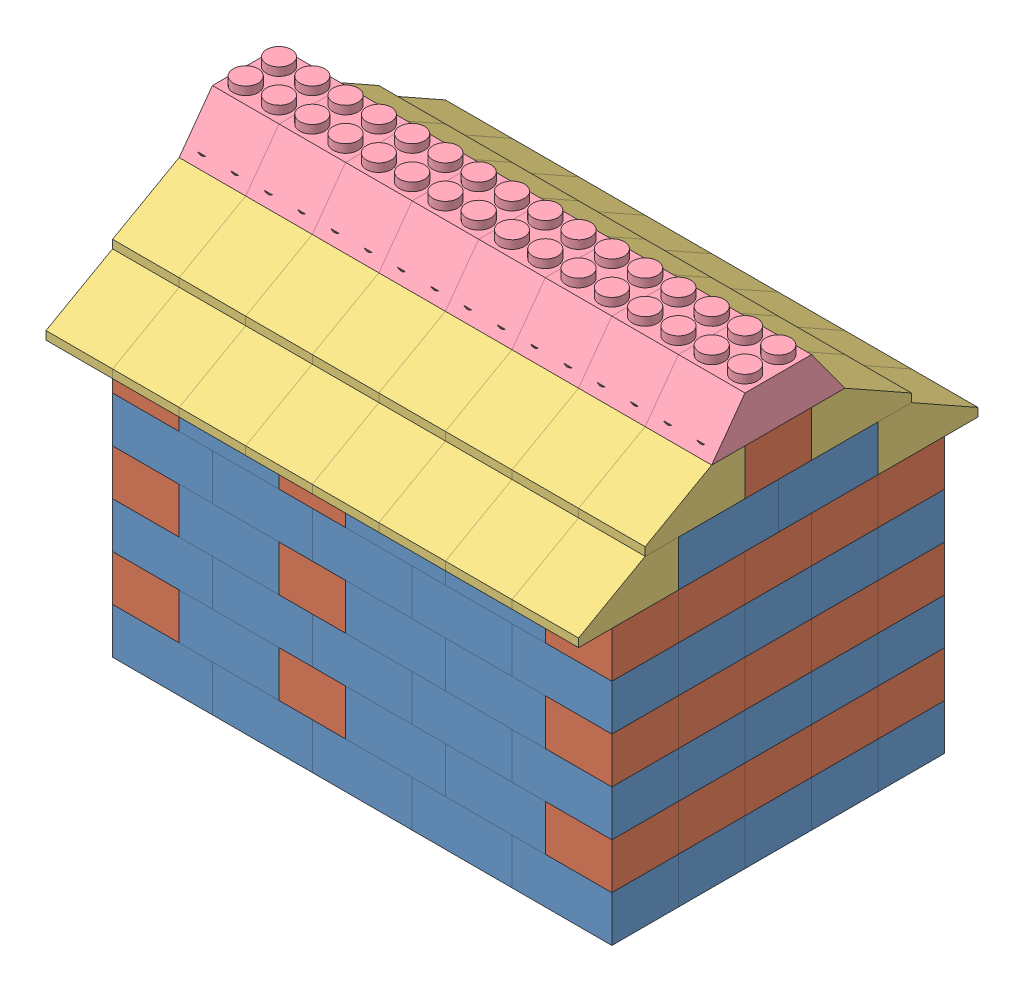
SolidWorks assembly huisje, configuration Default. Lengths in mm.
Overall size (128 101 96).
229 component instances, 4 part files, 42 mates.
Components (placement in the parent):
- lego blokje-1: lego blokje [Default] at origin size (24 13 16)
- lego blokje-2: lego blokje [Default] at (24 0 0) size (24 13 16)
- lego blokje-3: lego blokje [Default] at (48 0 0) size (24 13 16)
- lego blokje-4: lego blokje [Default] at (72 0 0) size (24 13 16)
- lego blokje-5: lego blokje [Default] at (96 0 0) size (24 13 16)
- vierkant blokje lego-3: vierkant blokje lego [Default] at (-4 16.5 -8) size (16 13 16)
- lego blokje-6: lego blokje [Default] at (16 11 0) size (24 13 16)
- vierkant blokje lego-4: vierkant blokje lego [Default] at (36 16.5 -8) size (16 13 16)
- lego blokje-7: lego blokje [Default] at (56 11 0) size (24 13 16)
- lego blokje-8: lego blokje [Default] at (80 11 0) size (24 13 16)
- vierkant blokje lego-5: vierkant blokje lego [Default] at (100 16.5 -8) size (16 13 16)
- lego blokje-9: lego blokje [Default] at (96 22 0) size (24 13 16)
- lego blokje-10: lego blokje [Default] at (96 44 0) size (24 13 16)
- lego blokje-11: lego blokje [Default] at (24 22 0) size (24 13 16)
- lego blokje-12: lego blokje [Default] at (24 44 0) size (24 13 16)
- lego blokje-13: lego blokje [Default] at (48 22 0) size (24 13 16)
- lego blokje-14: lego blokje [Default] at (48 44 0) size (24 13 16)
- lego blokje-15: lego blokje [Default] at (72 22 0) size (24 13 16)
- lego blokje-16: lego blokje [Default] at (72 44 0) size (24 13 16)
- vierkant blokje lego-6: vierkant blokje lego [Default] at (100 38.5 -8) size (16 13 16)
- vierkant blokje lego-7: vierkant blokje lego [Default] at (100 60.5 -8) size (16 13 16)
- vierkant blokje lego-8: vierkant blokje lego [Default] at (36 38.5 -8) size (16 13 16)
- vierkant blokje lego-9: vierkant blokje lego [Default] at (36 60.5 -8) size (16 13 16)
- lego blokje-17: lego blokje [Default] at (0 22 0) size (24 13 16)
- lego blokje-18: lego blokje [Default] at (0 44 0) size (24 13 16)
- vierkant blokje lego-10: vierkant blokje lego [Default] at (-4 38.5 -8) size (16 13 16)
- vierkant blokje lego-11: vierkant blokje lego [Default] at (-4 60.5 -8) size (16 13 16)
- lego blokje-19: lego blokje [Default] at (16 33 0) size (24 13 16)
- lego blokje-20: lego blokje [Default] at (16 55 0) size (24 13 16)
- lego blokje-21: lego blokje [Default] at (56 33 0) size (24 13 16)
- lego blokje-22: lego blokje [Default] at (56 55 0) size (24 13 16)
- lego blokje-23: lego blokje [Default] at (80 33 0) size (24 13 16)
- lego blokje-24: lego blokje [Default] at (80 55 0) size (24 13 16)
- lego blokje-25: lego blokje [Default] at (96 0 -16) size (24 13 16)
- lego blokje-26: lego blokje [Default] at (96 0 -32) size (24 13 16)
- lego blokje-27: lego blokje [Default] at (96 0 -48) size (24 13 16)
- lego blokje-28: lego blokje [Default] at (96 0 -64) size (24 13 16)
- lego blokje-29: lego blokje [Default] at (24 0 -16) size (24 13 16)
- lego blokje-30: lego blokje [Default] at (24 0 -32) size (24 13 16)
- lego blokje-31: lego blokje [Default] at (24 0 -48) size (24 13 16)
- lego blokje-32: lego blokje [Default] at (24 0 -64) size (24 13 16)
- lego blokje-33: lego blokje [Default] at (48 0 -16) size (24 13 16)
- lego blokje-34: lego blokje [Default] at (48 0 -32) size (24 13 16)
- lego blokje-35: lego blokje [Default] at (48 0 -48) size (24 13 16)
- lego blokje-36: lego blokje [Default] at (48 0 -64) size (24 13 16)
- lego blokje-37: lego blokje [Default] at (72 0 -16) size (24 13 16)
- lego blokje-38: lego blokje [Default] at (72 0 -32) size (24 13 16)
- lego blokje-39: lego blokje [Default] at (72 0 -48) size (24 13 16)
- lego blokje-40: lego blokje [Default] at (72 0 -64) size (24 13 16)
- lego blokje-41: lego blokje [Default] at (96 22 -16) size (24 13 16)
- lego blokje-42: lego blokje [Default] at (96 22 -32) size (24 13 16)
- lego blokje-43: lego blokje [Default] at (96 22 -48) size (24 13 16)
- lego blokje-44: lego blokje [Default] at (96 22 -64) size (24 13 16)
- lego blokje-45: lego blokje [Default] at (96 44 -16) size (24 13 16)
- lego blokje-46: lego blokje [Default] at (96 44 -32) size (24 13 16)
- lego blokje-47: lego blokje [Default] at (96 44 -48) size (24 13 16)
- lego blokje-48: lego blokje [Default] at (96 44 -64) size (24 13 16)
- lego blokje-49: lego blokje [Default] at (24 22 -16) size (24 13 16)
- lego blokje-50: lego blokje [Default] at (24 22 -32) size (24 13 16)
- lego blokje-51: lego blokje [Default] at (24 22 -48) size (24 13 16)
- lego blokje-52: lego blokje [Default] at (24 22 -64) size (24 13 16)
- vierkant blokje lego-12: vierkant blokje lego [Default] at (100 16.5 -24) size (16 13 16)
- vierkant blokje lego-13: vierkant blokje lego [Default] at (100 16.5 -40) size (16 13 16)
- vierkant blokje lego-14: vierkant blokje lego [Default] at (100 16.5 -56) size (16 13 16)
- vierkant blokje lego-15: vierkant blokje lego [Default] at (100 16.5 -72) size (16 13 16)
- vierkant blokje lego-16: vierkant blokje lego [Default] at (36 16.5 -24) size (16 13 16)
- vierkant blokje lego-17: vierkant blokje lego [Default] at (36 16.5 -40) size (16 13 16)
- vierkant blokje lego-18: vierkant blokje lego [Default] at (36 16.5 -56) size (16 13 16)
- vierkant blokje lego-19: vierkant blokje lego [Default] at (36 16.5 -72) size (16 13 16)
- lego blokje-53: lego blokje [Default] at (0 0 -16) size (24 13 16)
- lego blokje-54: lego blokje [Default] at (0 0 -32) size (24 13 16)
- lego blokje-55: lego blokje [Default] at (0 0 -48) size (24 13 16)
- lego blokje-56: lego blokje [Default] at (0 0 -64) size (24 13 16)
- vierkant blokje lego-20: vierkant blokje lego [Default] at (-4 16.5 -24) size (16 13 16)
- vierkant blokje lego-21: vierkant blokje lego [Default] at (-4 16.5 -40) size (16 13 16)
- vierkant blokje lego-22: vierkant blokje lego [Default] at (-4 16.5 -56) size (16 13 16)
- vierkant blokje lego-23: vierkant blokje lego [Default] at (-4 16.5 -72) size (16 13 16)
- lego blokje-57: lego blokje [Default] at (16 11 -16) size (24 13 16)
- lego blokje-58: lego blokje [Default] at (16 11 -32) size (24 13 16)
- lego blokje-59: lego blokje [Default] at (16 11 -48) size (24 13 16)
- lego blokje-60: lego blokje [Default] at (16 11 -64) size (24 13 16)
- lego blokje-61: lego blokje [Default] at (56 11 -16) size (24 13 16)
- lego blokje-62: lego blokje [Default] at (56 11 -32) size (24 13 16)
- lego blokje-63: lego blokje [Default] at (56 11 -48) size (24 13 16)
- lego blokje-64: lego blokje [Default] at (56 11 -64) size (24 13 16)
- lego blokje-65: lego blokje [Default] at (80 11 -16) size (24 13 16)
- lego blokje-66: lego blokje [Default] at (80 11 -32) size (24 13 16)
- lego blokje-67: lego blokje [Default] at (80 11 -48) size (24 13 16)
- lego blokje-68: lego blokje [Default] at (80 11 -64) size (24 13 16)
- lego blokje-69: lego blokje [Default] at (16 33 -16) size (24 13 16)
- lego blokje-70: lego blokje [Default] at (16 33 -32) size (24 13 16)
- lego blokje-71: lego blokje [Default] at (16 33 -48) size (24 13 16)
- lego blokje-72: lego blokje [Default] at (16 33 -64) size (24 13 16)
- lego blokje-73: lego blokje [Default] at (80 55 -16) size (24 13 16)
- lego blokje-74: lego blokje [Default] at (80 55 -32) size (24 13 16)
- lego blokje-75: lego blokje [Default] at (80 55 -48) size (24 13 16)
- lego blokje-76: lego blokje [Default] at (80 55 -64) size (24 13 16)
- vierkant blokje lego-24: vierkant blokje lego [Default] at (-4 38.5 -24) size (16 13 16)
- vierkant blokje lego-25: vierkant blokje lego [Default] at (-4 38.5 -40) size (16 13 16)
- vierkant blokje lego-26: vierkant blokje lego [Default] at (-4 38.5 -56) size (16 13 16)
- vierkant blokje lego-27: vierkant blokje lego [Default] at (-4 38.5 -72) size (16 13 16)
- lego blokje-77: lego blokje [Default] at (72 22 -16) size (24 13 16)
- lego blokje-78: lego blokje [Default] at (72 22 -32) size (24 13 16)
- lego blokje-79: lego blokje [Default] at (72 22 -48) size (24 13 16)
- lego blokje-80: lego blokje [Default] at (72 22 -64) size (24 13 16)
- lego blokje-81: lego blokje [Default] at (48 22 -16) size (24 13 16)
- lego blokje-82: lego blokje [Default] at (48 22 -32) size (24 13 16)
- lego blokje-83: lego blokje [Default] at (48 22 -48) size (24 13 16)
- lego blokje-84: lego blokje [Default] at (48 22 -64) size (24 13 16)
- lego blokje-85: lego blokje [Default] at (0 22 -16) size (24 13 16)
- lego blokje-86: lego blokje [Default] at (0 22 -32) size (24 13 16)
- lego blokje-87: lego blokje [Default] at (0 22 -48) size (24 13 16)
- lego blokje-88: lego blokje [Default] at (0 22 -64) size (24 13 16)
- vierkant blokje lego-28: vierkant blokje lego [Default] at (36 60.5 -24) size (16 13 16)
- vierkant blokje lego-29: vierkant blokje lego [Default] at (36 60.5 -40) size (16 13 16)
- vierkant blokje lego-30: vierkant blokje lego [Default] at (36 60.5 -56) size (16 13 16)
- vierkant blokje lego-31: vierkant blokje lego [Default] at (36 60.5 -72) size (16 13 16)
- vierkant blokje lego-32: vierkant blokje lego [Default] at (100 38.5 -24) size (16 13 16)
- vierkant blokje lego-33: vierkant blokje lego [Default] at (100 38.5 -40) size (16 13 16)
- vierkant blokje lego-34: vierkant blokje lego [Default] at (100 38.5 -56) size (16 13 16)
- vierkant blokje lego-35: vierkant blokje lego [Default] at (100 38.5 -72) size (16 13 16)
- lego blokje-89: lego blokje [Default] at (0 44 -16) size (24 13 16)
- lego blokje-90: lego blokje [Default] at (0 44 -32) size (24 13 16)
- lego blokje-91: lego blokje [Default] at (0 44 -48) size (24 13 16)
- lego blokje-92: lego blokje [Default] at (0 44 -64) size (24 13 16)
- vierkant blokje lego-36: vierkant blokje lego [Default] at (-4 60.5 -24) size (16 13 16)
- vierkant blokje lego-37: vierkant blokje lego [Default] at (-4 60.5 -40) size (16 13 16)
- vierkant blokje lego-38: vierkant blokje lego [Default] at (-4 60.5 -56) size (16 13 16)
- vierkant blokje lego-39: vierkant blokje lego [Default] at (-4 60.5 -72) size (16 13 16)
- lego blokje-93: lego blokje [Default] at (56 33 -16) size (24 13 16)
- lego blokje-94: lego blokje [Default] at (56 33 -32) size (24 13 16)
- lego blokje-95: lego blokje [Default] at (56 33 -48) size (24 13 16)
- lego blokje-96: lego blokje [Default] at (56 33 -64) size (24 13 16)
- lego blokje-97: lego blokje [Default] at (48 44 -16) size (24 13 16)
- lego blokje-98: lego blokje [Default] at (48 44 -32) size (24 13 16)
- lego blokje-99: lego blokje [Default] at (48 44 -48) size (24 13 16)
- lego blokje-100: lego blokje [Default] at (48 44 -64) size (24 13 16)
- vierkant blokje lego-40: vierkant blokje lego [Default] at (100 60.5 -24) size (16 13 16)
- vierkant blokje lego-41: vierkant blokje lego [Default] at (100 60.5 -40) size (16 13 16)
- vierkant blokje lego-42: vierkant blokje lego [Default] at (100 60.5 -56) size (16 13 16)
- vierkant blokje lego-43: vierkant blokje lego [Default] at (100 60.5 -72) size (16 13 16)
- lego blokje-101: lego blokje [Default] at (16 55 -16) size (24 13 16)
- lego blokje-102: lego blokje [Default] at (16 55 -32) size (24 13 16)
- lego blokje-103: lego blokje [Default] at (16 55 -48) size (24 13 16)
- lego blokje-104: lego blokje [Default] at (16 55 -64) size (24 13 16)
- lego blokje-105: lego blokje [Default] at (56 55 -16) size (24 13 16)
- lego blokje-106: lego blokje [Default] at (56 55 -32) size (24 13 16)
- lego blokje-107: lego blokje [Default] at (56 55 -48) size (24 13 16)
- lego blokje-108: lego blokje [Default] at (56 55 -64) size (24 13 16)
- vierkant blokje lego-44: vierkant blokje lego [Default] at (36 38.5 -24) size (16 13 16)
- vierkant blokje lego-45: vierkant blokje lego [Default] at (36 38.5 -40) size (16 13 16)
- vierkant blokje lego-46: vierkant blokje lego [Default] at (36 38.5 -56) size (16 13 16)
- vierkant blokje lego-47: vierkant blokje lego [Default] at (36 38.5 -72) size (16 13 16)
- lego blokje-109: lego blokje [Default] at (24 44 -16) size (24 13 16)
- lego blokje-110: lego blokje [Default] at (24 44 -32) size (24 13 16)
- lego blokje-111: lego blokje [Default] at (24 44 -48) size (24 13 16)
- lego blokje-112: lego blokje [Default] at (24 44 -64) size (24 13 16)
- lego blokje-113: lego blokje [Default] at (72 44 -16) size (24 13 16)
- lego blokje-114: lego blokje [Default] at (72 44 -32) size (24 13 16)
- lego blokje-115: lego blokje [Default] at (72 44 -48) size (24 13 16)
- lego blokje-116: lego blokje [Default] at (72 44 -64) size (24 13 16)
- lego blokje-117: lego blokje [Default] at (80 33 -16) size (24 13 16)
- lego blokje-118: lego blokje [Default] at (80 33 -32) size (24 13 16)
- lego blokje-119: lego blokje [Default] at (80 33 -48) size (24 13 16)
- lego blokje-120: lego blokje [Default] at (80 33 -64) size (24 13 16)
- lego blokje schuin-1: lego blokje schuin [Default] at (108 66 -8) x (0 0 1) z (-1 0 0) size (24 13 16)
- lego blokje-121: lego blokje [Default] at (100 66 -20) x (0 0 1) z (-1 0 0) size (24 13 16)
- lego blokje-122: lego blokje [Default] at (100 66 -44) x (0 0 1) z (-1 0 0) size (24 13 16)
- lego blokje schuin-2: lego blokje schuin [Default] at (92 66 -56) x (0 0 -1) z (1 0 0) size (24 13 16)
- lego blokje schuin-4: lego blokje schuin [Default] at (108 77 -24) x (0 0 1) z (-1 0 0) size (24 13 16)
- lego blokje schuin-5: lego blokje schuin [Default] at (92 77 -40) x (0 0 -1) z (1 0 0) size (24 13 16)
- vierkant blokje lego-49: vierkant blokje lego [Default] at (100 82.5 -40) size (16 13 16)
- 2 schuinen kanten-2: 2 schuinen kanten [Default] at (92 93.5 -32) x (0 0 -1) z (1 0 0) size (32 13 16)
- 2 schuinen kanten-3: 2 schuinen kanten [Default] at (76 93.5 -32) x (0 0 -1) z (1 0 0) size (32 13 16)
- 2 schuinen kanten-4: 2 schuinen kanten [Default] at (60 93.5 -32) x (0 0 -1) z (1 0 0) size (32 13 16)
- 2 schuinen kanten-5: 2 schuinen kanten [Default] at (44 93.5 -32) x (0 0 -1) z (1 0 0) size (32 13 16)
- 2 schuinen kanten-6: 2 schuinen kanten [Default] at (28 93.5 -32) x (0 0 -1) z (1 0 0) size (32 13 16)
- 2 schuinen kanten-7: 2 schuinen kanten [Default] at (12 93.5 -32) x (0 0 -1) z (1 0 0) size (32 13 16)
- 2 schuinen kanten-8: 2 schuinen kanten [Default] at (-4 93.5 -32) x (0 0 -1) z (1 0 0) size (32 13 16)
- 2 schuinen kanten-9: 2 schuinen kanten [Default] at (-20 93.5 -32) x (0 0 -1) z (1 0 0) size (32 13 16)
- lego blokje schuin-6: lego blokje schuin [Default] at (92 77 -24) x (0 0 1) z (-1 0 0) size (24 13 16)
- lego blokje schuin-7: lego blokje schuin [Default] at (76 77 -24) x (0 0 1) z (-1 0 0) size (24 13 16)
- lego blokje schuin-8: lego blokje schuin [Default] at (60 77 -24) x (0 0 1) z (-1 0 0) size (24 13 16)
- lego blokje schuin-9: lego blokje schuin [Default] at (44 77 -24) x (0 0 1) z (-1 0 0) size (24 13 16)
- lego blokje schuin-10: lego blokje schuin [Default] at (28 77 -24) x (0 0 1) z (-1 0 0) size (24 13 16)
- lego blokje schuin-11: lego blokje schuin [Default] at (12 77 -24) x (0 0 1) z (-1 0 0) size (24 13 16)
- lego blokje schuin-12: lego blokje schuin [Default] at (-4 77 -24) x (0 0 1) z (-1 0 0) size (24 13 16)
- vierkant blokje lego-50: vierkant blokje lego [Default] at (84 82.5 -40) size (16 13 16)
- vierkant blokje lego-51: vierkant blokje lego [Default] at (68 82.5 -40) size (16 13 16)
- vierkant blokje lego-52: vierkant blokje lego [Default] at (52 82.5 -40) size (16 13 16)
- vierkant blokje lego-53: vierkant blokje lego [Default] at (36 82.5 -40) size (16 13 16)
- vierkant blokje lego-54: vierkant blokje lego [Default] at (20 82.5 -40) size (16 13 16)
- vierkant blokje lego-55: vierkant blokje lego [Default] at (4 82.5 -40) size (16 13 16)
- vierkant blokje lego-56: vierkant blokje lego [Default] at (-12 82.5 -40) size (16 13 16)
- lego blokje schuin-13: lego blokje schuin [Default] at (76 77 -40) x (0 0 -1) z (1 0 0) size (24 13 16)
- lego blokje schuin-14: lego blokje schuin [Default] at (60 77 -40) x (0 0 -1) z (1 0 0) size (24 13 16)
- lego blokje schuin-15: lego blokje schuin [Default] at (44 77 -40) x (0 0 -1) z (1 0 0) size (24 13 16)
- lego blokje schuin-16: lego blokje schuin [Default] at (28 77 -40) x (0 0 -1) z (1 0 0) size (24 13 16)
- lego blokje schuin-17: lego blokje schuin [Default] at (12 77 -40) x (0 0 -1) z (1 0 0) size (24 13 16)
- lego blokje schuin-18: lego blokje schuin [Default] at (-4 77 -40) x (0 0 -1) z (1 0 0) size (24 13 16)
- lego blokje schuin-19: lego blokje schuin [Default] at (-20 77 -40) x (0 0 -1) z (1 0 0) size (24 13 16)
- lego blokje schuin-20: lego blokje schuin [Default] at (76 66 -56) x (0 0 -1) z (1 0 0) size (24 13 16)
- lego blokje schuin-21: lego blokje schuin [Default] at (60 66 -56) x (0 0 -1) z (1 0 0) size (24 13 16)
- lego blokje schuin-22: lego blokje schuin [Default] at (44 66 -56) x (0 0 -1) z (1 0 0) size (24 13 16)
- lego blokje schuin-23: lego blokje schuin [Default] at (28 66 -56) x (0 0 -1) z (1 0 0) size (24 13 16)
- lego blokje schuin-24: lego blokje schuin [Default] at (12 66 -56) x (0 0 -1) z (1 0 0) size (24 13 16)
- lego blokje schuin-25: lego blokje schuin [Default] at (-4 66 -56) x (0 0 -1) z (1 0 0) size (24 13 16)
- lego blokje schuin-26: lego blokje schuin [Default] at (-20 66 -56) x (0 0 -1) z (1 0 0) size (24 13 16)
- lego blokje-123: lego blokje [Default] at (84 66 -44) x (0 0 1) z (-1 0 0) size (24 13 16)
- lego blokje-124: lego blokje [Default] at (68 66 -44) x (0 0 1) z (-1 0 0) size (24 13 16)
- lego blokje-125: lego blokje [Default] at (52 66 -44) x (0 0 1) z (-1 0 0) size (24 13 16)
- lego blokje-126: lego blokje [Default] at (36 66 -44) x (0 0 1) z (-1 0 0) size (24 13 16)
- lego blokje-127: lego blokje [Default] at (20 66 -44) x (0 0 1) z (-1 0 0) size (24 13 16)
- lego blokje-128: lego blokje [Default] at (4 66 -44) x (0 0 1) z (-1 0 0) size (24 13 16)
- lego blokje-129: lego blokje [Default] at (-12 66 -44) x (0 0 1) z (-1 0 0) size (24 13 16)
- lego blokje-130: lego blokje [Default] at (84 66 -20) x (0 0 1) z (-1 0 0) size (24 13 16)
- lego blokje-131: lego blokje [Default] at (68 66 -20) x (0 0 1) z (-1 0 0) size (24 13 16)
- lego blokje-132: lego blokje [Default] at (52 66 -20) x (0 0 1) z (-1 0 0) size (24 13 16)
- lego blokje-133: lego blokje [Default] at (36 66 -20) x (0 0 1) z (-1 0 0) size (24 13 16)
- lego blokje-134: lego blokje [Default] at (20 66 -20) x (0 0 1) z (-1 0 0) size (24 13 16)
- lego blokje-135: lego blokje [Default] at (4 66 -20) x (0 0 1) z (-1 0 0) size (24 13 16)
- lego blokje-136: lego blokje [Default] at (-12 66 -20) x (0 0 1) z (-1 0 0) size (24 13 16)
- lego blokje schuin-27: lego blokje schuin [Default] at (92 66 -8) x (0 0 1) z (-1 0 0) size (24 13 16)
- lego blokje schuin-28: lego blokje schuin [Default] at (76 66 -8) x (0 0 1) z (-1 0 0) size (24 13 16)
- lego blokje schuin-29: lego blokje schuin [Default] at (60 66 -8) x (0 0 1) z (-1 0 0) size (24 13 16)
- lego blokje schuin-30: lego blokje schuin [Default] at (44 66 -8) x (0 0 1) z (-1 0 0) size (24 13 16)
- lego blokje schuin-31: lego blokje schuin [Default] at (28 66 -8) x (0 0 1) z (-1 0 0) size (24 13 16)
- lego blokje schuin-32: lego blokje schuin [Default] at (12 66 -8) x (0 0 1) z (-1 0 0) size (24 13 16)
- lego blokje schuin-33: lego blokje schuin [Default] at (-4 66 -8) x (0 0 1) z (-1 0 0) size (24 13 16)
Mates (geometry in assembly coordinates):
- Coincident5: coincident aligned: plane of lego blokje-1 through (-12 11 8) normal (-1 0 0); plane of vierkant blokje lego-3 through (-12 11 8) normal (-1 0 0)
- Coincident6: coincident aligned: plane of lego blokje-1 through (12 11 8) normal (0 0 1); plane of vierkant blokje lego-3 through (-4 16.5 8) normal (0 0 1)
- Coincident7: coincident anti-aligned: plane of lego blokje-1 through (0 11 0) normal (0 1 0); plane of vierkant blokje lego-3 through (4 11 8) normal (0 -1 0)
- Coincident8: coincident anti-aligned: plane of vierkant blokje lego-3 through (4 11 8) normal (1 0 0); plane of lego blokje-6 through (4 22 8) normal (-1 0 0)
- Coincident9: coincident aligned: plane of lego blokje-2 through (36 11 8) normal (0 0 1); plane of lego blokje-6 through (28 22 8) normal (0 0 1)
- Coincident10: coincident anti-aligned: plane of lego blokje-2 through (24 11 0) normal (0 1 0); plane of lego blokje-6 through (16 11 0) normal (0 -1 0)
- Coincident11: coincident anti-aligned: plane of lego blokje-6 through (28 22 8) normal (1 0 0); plane of vierkant blokje lego-4 through (28 11 8) normal (-1 0 0)
- Coincident12: coincident aligned: plane of lego blokje-2 through (36 11 8) normal (0 0 1); plane of vierkant blokje lego-4 through (36 16.5 8) normal (0 0 1)
- Coincident13: coincident anti-aligned: plane of lego blokje-2 through (24 11 0) normal (0 1 0); plane of vierkant blokje lego-4 through (44 11 8) normal (0 -1 0)
- Coincident14: coincident anti-aligned: plane of vierkant blokje lego-4 through (44 11 8) normal (1 0 0); plane of lego blokje-7 through (44 22 8) normal (-1 0 0)
- Coincident15: coincident aligned: plane of lego blokje-3 through (60 11 8) normal (0 0 1); plane of lego blokje-7 through (68 22 8) normal (0 0 1)
- Coincident16: coincident anti-aligned: plane of lego blokje-3 through (48 11 0) normal (0 1 0); plane of lego blokje-7 through (56 11 0) normal (0 -1 0)
- Coincident17: coincident anti-aligned: plane of lego blokje-7 through (68 22 8) normal (1 0 0); plane of lego blokje-8 through (68 22 8) normal (-1 0 0)
- Coincident18: coincident aligned: plane of lego blokje-4 through (84 11 8) normal (0 0 1); plane of lego blokje-8 through (92 22 8) normal (0 0 1)
- Coincident19: coincident anti-aligned: plane of lego blokje-4 through (72 11 0) normal (0 1 0); plane of lego blokje-8 through (80 11 0) normal (0 -1 0)
- Coincident20: coincident anti-aligned: plane of lego blokje-8 through (92 22 8) normal (1 0 0); plane of vierkant blokje lego-5 through (92 11 8) normal (-1 0 0)
- Coincident21: coincident aligned: plane of lego blokje-5 through (108 11 8) normal (0 0 1); plane of vierkant blokje lego-5 through (100 16.5 8) normal (0 0 1)
- Coincident22: coincident anti-aligned: plane of lego blokje-5 through (96 11 0) normal (0 1 0); plane of vierkant blokje lego-5 through (108 11 8) normal (0 -1 0)
- Coincident25: coincident anti-aligned: line of vierkant blokje lego-7 through (108 66 8) axis (0 0 -1); line of lego blokje schuin-1 through (108 66 -8) axis (0 0 1)
- Coincident26: coincident: line of vierkant blokje lego-7 through (108 66 -8) axis (-1 0 0); plane of lego blokje schuin-1 through (92 66 -8) normal (0 0 -1)
- Coincident34: coincident anti-aligned: plane of lego blokje schuin-1 through (92 66 -8) normal (0 0 -1); plane of lego blokje-121 through (92 77 -8) normal (0 0 1)
- Coincident35: coincident aligned: plane of lego blokje schuin-1 through (92 66 -8) normal (-1 0 0); plane of lego blokje-121 through (92 77 -8) normal (-1 0 0)
- Coincident36: coincident: plane of vierkant blokje lego-41 through (108 66 -24) normal (0 1 0); line of lego blokje-121 through (108 66 -32) axis (-1 0 0)
- Coincident37: coincident anti-aligned: plane of lego blokje-121 through (92 77 -32) normal (0 0 -1); plane of lego blokje-122 through (92 77 -32) normal (0 0 1)
- Coincident38: coincident aligned: plane of lego blokje-121 through (92 77 -8) normal (-1 0 0); plane of lego blokje-122 through (92 77 -32) normal (-1 0 0)
- Coincident39: coincident: plane of vierkant blokje lego-42 through (108 66 -40) normal (0 1 0); line of lego blokje-122 through (108 66 -56) axis (-1 0 0)
- Coincident40: coincident anti-aligned: plane of lego blokje-122 through (92 77 -56) normal (0 0 -1); plane of lego blokje schuin-2 through (108 66 -56) normal (0 0 1)
- Coincident41: coincident aligned: plane of lego blokje-122 through (108 77 -32) normal (1 0 0); plane of lego blokje schuin-2 through (108 66 -56) normal (1 0 0)
- Coincident42: coincident anti-aligned: plane of vierkant blokje lego-43 through (108 66 -56) normal (0 1 0); plane of lego blokje schuin-2 through (108 66 -80) normal (0 -1 0)
- Coincident56: coincident anti-aligned: plane of lego blokje-121 through (100 77 -20) normal (0 1 0); plane of lego blokje schuin-4 through (92 77 0) normal (0 -1 0)
- Coincident57: coincident: line of lego blokje schuin-1 through (92 77 0) axis (1 0 0); plane of lego blokje schuin-4 through (92 79 0) normal (0 0 1)
- Coincident58: coincident aligned: plane of lego blokje-121 through (108 77 -8) normal (1 0 0); plane of lego blokje schuin-4 through (108 77 -24) normal (1 0 0)
- Coincident59: coincident anti-aligned: plane of lego blokje-122 through (100 77 -44) normal (0 1 0); plane of lego blokje schuin-5 through (108 77 -64) normal (0 -1 0)
- Coincident60: coincident aligned: plane of lego blokje-122 through (108 77 -32) normal (1 0 0); plane of lego blokje schuin-5 through (108 77 -40) normal (1 0 0)
- Coincident61: coincident: line of lego blokje schuin-2 through (108 77 -64) axis (-1 0 0); plane of lego blokje schuin-5 through (108 79 -64) normal (0 0 -1)
- Coincident62: coincident aligned: plane of lego blokje-121 through (108 77 -8) normal (1 0 0); plane of vierkant blokje lego-49 through (108 77 -24) normal (1 0 0)
- Coincident63: coincident: plane of lego blokje schuin-4 through (92 77 -24) normal (0 0 -1); line of vierkant blokje lego-49 through (108 88 -24) axis (-1 0 0)
- Coincident65: coincident anti-aligned: plane of lego blokje-121 through (100 77 -20) normal (0 1 0); plane of vierkant blokje lego-49 through (108 77 -24) normal (0 -1 0)
- Coincident66: coincident: plane of lego blokje schuin-5 through (108 88 -40) normal (0 1 0); line of 2 schuinen kanten-2 through (108 88 -48) axis (-1 0 0)
- Coincident72: coincident anti-aligned: plane of vierkant blokje lego-49 through (108 88 -24) normal (0 1 0); plane of 2 schuinen kanten-2 through (108 88 -40) normal (0 -1 0)
- Coincident73: coincident anti-aligned: line of lego blokje schuin-4 through (92 88 -16) axis (1 0 0); line of 2 schuinen kanten-2 through (108 88 -16) axis (-1 0 0)
- Coincident74: coincident aligned: plane of vierkant blokje lego-49 through (108 77 -24) normal (1 0 0); plane of 2 schuinen kanten-2 through (108 93.5 -32) normal (1 0 0)
